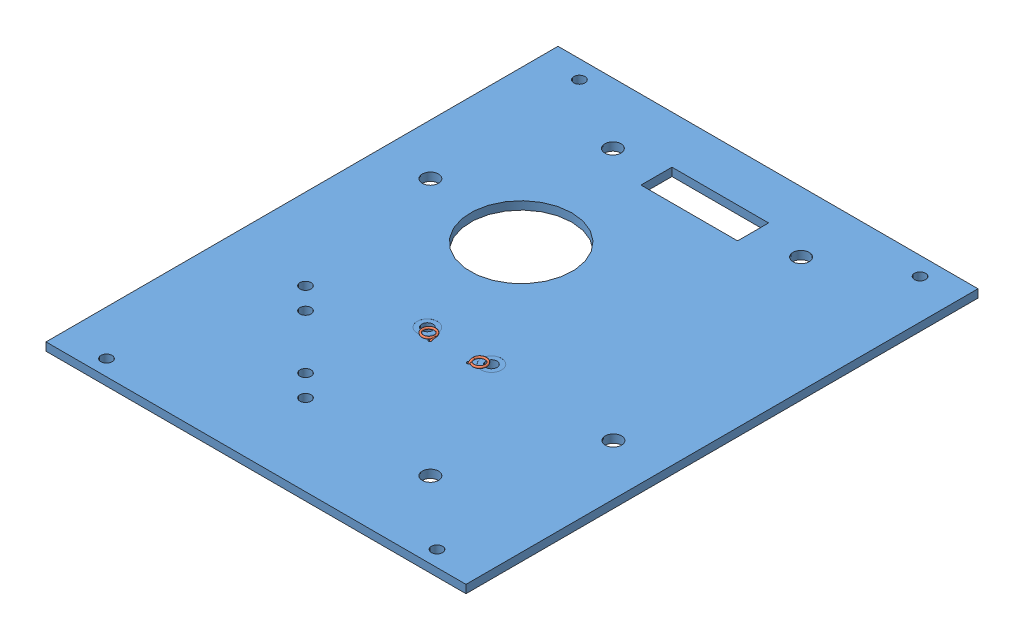
SolidWorks assembly Assem2, configuration ﾃﾞﾌｫﾙﾄ. Lengths in mm.
Overall size (82.6 7.41 100.7).
2 component instances, 2 part files, 3 mates.
Components (placement in the parent):
- B3_-X_panel_dipole-1: B3_-X_panel_dipole [Default] at (-17.5462 -0.0688 81.8125) size (82.6 1.6 100.7)
- B3_nichrome_wire-1: B3_nichrome_wire [Default] at (6.1938 0.7312 113.05) x (1 0 0) z (0 1 0) size (12.8 3.93 7.41)
Mates (geometry in assembly coordinates):
- 同心円1: concentric anti-aligned: cylinder of B3_-X_panel_dipole-1 through (9.9938 -8.4688 113.05) axis (0 1 0) radius 0.3; cylinder of B3_nichrome_wire-1 through (9.9938 0.7312 113.05) axis (0 -1 0) radius 0.2
- 同心円2: concentric anti-aligned: cylinder of B3_-X_panel_dipole-1 through (2.3938 -8.4688 113.05) axis (0 1 0) radius 0.3; cylinder of B3_nichrome_wire-1 through (2.3938 0.7312 113.05) axis (0 -1 0) radius 0.2
- 正接1: tangent: plane of B3_-X_panel_dipole-1 through (-17.5462 1.5312 81.8125) normal (0 1 0); torus of B3_nichrome_wire-1
